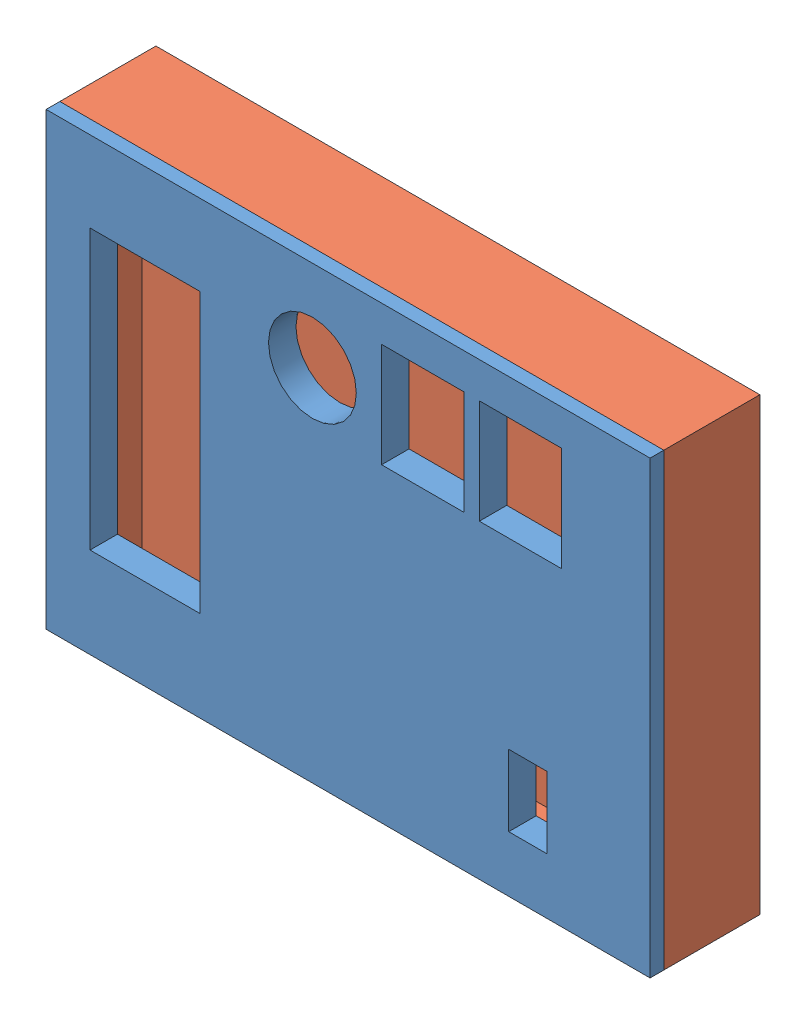
SolidWorks assembly Phase_B_Encloser_ASM, configuration Default. Lengths in mm.
Overall size (110 82 20).
50 component instances, 3 part files, 3 mates.
Components (placement in the parent):
- R_0805_2012Metric.STEP-1: R_0805_2012Metric.STEP [Default] at (136.75 -75.9525 1.63) x (0 1 0) z (0 0 1) size (2 1.2 0.45) (suppressed, hidden)
- PinSocket_2x03_P2.54mm_Vertical.STEP-1: PinSocket_2x03_P2.54mm_Vertical.STEP [Default] at (166.9225 -107.335 1.13) x (-1 0 0) z (0 0 -1) size (5.08 7.62 10.1) (suppressed, hidden)
- C_0603_1608Metric.STEP-1: C_0603_1608Metric.STEP [Default] at (175.1083 -95.3579 1.63) x (0 1 0) z (0 0 1) size (1.6 0.8 0.8) (suppressed, hidden)
- C_0603_1608Metric.STEP-2: C_0603_1608Metric.STEP [Default] at (167.3681 -95.3139 1.63) x (0 1 0) z (0 0 1) size (1.6 0.8 0.8) (suppressed, hidden)
- R_0603_1608Metric.STEP-1: R_0603_1608Metric.STEP [Default] at (178.1154 -121.5005 1.63) size (1.6 0.8 0.45) (suppressed, hidden)
- R_0805_2012Metric.STEP-2: R_0805_2012Metric.STEP [Default] at (164.6638 -86.8628 1.63) size (2 1.2 0.45) (suppressed, hidden)
- USB_Mini-B_Lumberg_2486_01_Horizontal.STEP-1: USB_Mini-B_Lumberg_2486_01_Horizontal.STEP [Default] at (156.7225 -119.07 1.63) size (9.9 9.21 5) (suppressed, hidden)
- SOT-23-5.STEP-1: SOT-23-5.STEP [Default] at (160.6831 -79.2295 1.63) x (0 -1 0) z (0 0 1) size (2.8 2.9 1.55) (suppressed, hidden)
- R_0805_2012Metric.STEP-3: R_0805_2012Metric.STEP [Default] at (124.46 -81.28 1.63) size (2 1.2 0.45) (suppressed, hidden)
- TQFP-44_10x10mm_P0.8mm.STEP-1: TQFP-44_10x10mm_P0.8mm.STEP [Default] at (154.94 -91.44 1.63) x (0 1 0) z (0 0 1) size (12 12 1.1) (suppressed, hidden)
- LED_0805_2012Metric.STEP-1: LED_0805_2012Metric.STEP [Default] at (136.66 -80.3425 1.63) x (0 1 0) z (0 0 1) size (2 1.25 1.1) (suppressed, hidden)
- C_0603_1608Metric.STEP-3: C_0603_1608Metric.STEP [Default] at (164.6143 -92.9198 1.63) size (1.6 0.8 0.8) (suppressed, hidden)
- CA56-12EWA.STEP-1: CA56-12EWA.STEP [Default] at (101.6 -81.28 1.63) size (19 50.3 12.2) (suppressed, hidden)
- C_0603_1608Metric.STEP-4: C_0603_1608Metric.STEP [Default] at (160.3412 -83.2998 1.63) x (-1 0 0) z (0 0 1) size (1.6 0.8 0.8) (suppressed, hidden)
- TSSOP-16_4.4x5mm_P0.65mm.STEP-1: TSSOP-16_4.4x5mm_P0.65mm.STEP [Default] at (137.16 -93.98 1.63) size (6.4 5 1.1) (suppressed, hidden)
- PTS125_SMD_Button.STEP-1: PTS125_SMD_Button.STEP [Default] at (177.0425 -64.155 1.63) x (0 1 0) z (1 0 0) size (12 4.3 15.3) (suppressed, hidden)
- C_0603_1608Metric.STEP-5: C_0603_1608Metric.STEP [Default] at (171.2411 -95.3579 1.63) x (0 1 0) z (0 0 1) size (1.6 0.8 0.8) (suppressed, hidden)
- R_0603_1608Metric.STEP-2: R_0603_1608Metric.STEP [Default] at (171.895 -101.6 1.63) size (1.6 0.8 0.45) (suppressed, hidden)
- C_0603_1608Metric.STEP-6: C_0603_1608Metric.STEP [Default] at (135.1928 -99.8408 1.63) x (-1 0 0) z (0 0 1) size (1.6 0.8 0.8) (suppressed, hidden)
- C_0805_2012Metric.STEP-1: C_0805_2012Metric.STEP [Default] at (177.4051 -95.4592 1.63) x (0 1 0) z (0 0 1) size (2 1.25 1.25) (suppressed, hidden)
- R_0805_2012Metric.STEP-4: R_0805_2012Metric.STEP [Default] at (124.46 -96.93 1.63) size (2 1.2 0.45) (suppressed, hidden)
- R_0805_2012Metric.STEP-5: R_0805_2012Metric.STEP [Default] at (124.46 -99.88 1.63) size (2 1.2 0.45) (suppressed, hidden)
- Buzzer_12x9.5RM7.6.STEP-1: Buzzer_12x9.5RM7.6.STEP [Default] at (139.7 -67.955 1.63) x (0 1 0) z (0 0 1) size (12 12 12.53) (suppressed, hidden)
- R_0603_1608Metric.STEP-3: R_0603_1608Metric.STEP [Default] at (164.621 -94.7272 1.63) x (-1 0 0) z (0 0 1) size (1.6 0.8 0.45) (suppressed, hidden)
- LED_0805_2012Metric.STEP-2: LED_0805_2012Metric.STEP [Default] at (139.7 -80.3425 1.63) x (0 1 0) z (0 0 1) size (2 1.25 1.1) (suppressed, hidden)
- R_0603_1608Metric.STEP-4: R_0603_1608Metric.STEP [Default] at (157.3461 -113.1038 1.63) x (0 1 0) z (0 0 1) size (1.6 0.8 0.45) (suppressed, hidden)
- R_0805_2012Metric.STEP-6: R_0805_2012Metric.STEP [Default] at (164.6674 -88.9903 1.63) size (2 1.2 0.45) (suppressed, hidden)
- C_0603_1608Metric.STEP-7: C_0603_1608Metric.STEP [Default] at (173.1422 -95.3579 1.63) x (0 1 0) z (0 0 1) size (1.6 0.8 0.8) (suppressed, hidden)
- C_0603_1608Metric.STEP-8: C_0603_1608Metric.STEP [Default] at (183.7777 -121.5005 1.63) size (1.6 0.8 0.8) (suppressed, hidden)
- Crystal_SMD_Abracon_ABM8G-4Pin_3.2x2.5mm.STEP-1: Crystal_SMD_Abracon_ABM8G-4Pin_3.2x2.5mm.STEP [Default] at (160.167 -106.8176 1.63) x (0 1 0) z (0 0 1) size (3.2 2.5 0.64) (suppressed, hidden)
- R_0805_2012Metric.STEP-7: R_0805_2012Metric.STEP [Default] at (124.46 -78.33 1.63) size (2 1.2 0.45) (suppressed, hidden)
- R_0805_2012Metric.STEP-8: R_0805_2012Metric.STEP [Default] at (139.7 -75.9525 1.63) x (0 1 0) z (0 0 1) size (2 1.2 0.45) (suppressed, hidden)
- R_0805_2012Metric.STEP-9: R_0805_2012Metric.STEP [Default] at (124.46 -93.98 1.63) size (2 1.2 0.45) (suppressed, hidden)
- C_0603_1608Metric.STEP-9: C_0603_1608Metric.STEP [Default] at (164.6119 -91.194 1.63) x (-1 0 0) z (0 0 1) size (1.6 0.8 0.8) (suppressed, hidden)
- C_0603_1608Metric.STEP-10: C_0603_1608Metric.STEP [Default] at (147.6552 -103.0061 1.63) x (0 -1 0) z (0 0 1) size (1.6 0.8 0.8) (suppressed, hidden)
- C_0603_1608Metric.STEP-11: C_0603_1608Metric.STEP [Default] at (164.2172 -77.2255 1.63) x (0 -1 0) z (0 0 1) size (1.6 0.8 0.8) (suppressed, hidden)
- C_0603_1608Metric.STEP-12: C_0603_1608Metric.STEP [Default] at (169.3071 -95.3345 1.63) x (0 1 0) z (0 0 1) size (1.6 0.8 0.8) (suppressed, hidden)
- C_0603_1608Metric.STEP-13: C_0603_1608Metric.STEP [Default] at (156.1028 -99.9047 1.63) x (0 1 0) z (0 0 1) size (1.6 0.8 0.8) (suppressed, hidden)
- SOT-23-6.STEP-1: SOT-23-6.STEP [Default] at (156.0168 -106.7769 1.63) x (0 1 0) z (0 0 1) size (2.8 2.9 1.55) (suppressed, hidden)
- R_0805_2012Metric.STEP-10: R_0805_2012Metric.STEP [Default] at (124.46 -91.03 1.63) size (2 1.2 0.45) (suppressed, hidden)
- R_0805_2012Metric.STEP-11: R_0805_2012Metric.STEP [Default] at (124.46 -84.23 1.63) size (2 1.2 0.45) (suppressed, hidden)
- C_0603_1608Metric.STEP-14: C_0603_1608Metric.STEP [Default] at (166.5378 -77.2117 1.63) x (0 -1 0) z (0 0 1) size (1.6 0.8 0.8) (suppressed, hidden)
- R_0805_2012Metric.STEP-12: R_0805_2012Metric.STEP [Default] at (124.46 -87.18 1.63) size (2 1.2 0.45) (suppressed, hidden)
- PinSocket_2x04_P2.54mm_Vertical.STEP-1: PinSocket_2x04_P2.54mm_Vertical.STEP [Default] at (179.5825 -109.875 1.63) size (5.08 10.16 10.1) (suppressed, hidden)
- LED_0805_2012Metric.STEP-3: LED_0805_2012Metric.STEP [Default] at (184.4796 -109.4399 1.63) size (2 1.25 1.1) (suppressed, hidden)
- R_0603_1608Metric.STEP-5: R_0603_1608Metric.STEP [Default] at (155.706 -113.0772 1.63) x (0 1 0) z (0 0 1) size (1.6 0.8 0.45) (suppressed, hidden)
- PTS125_SMD_Button.STEP-2: PTS125_SMD_Button.STEP [Default] at (159.2625 -64.155 1.63) x (0 1 0) z (1 0 0) size (12 4.3 15.3) (suppressed, hidden)
- PCB.STEP-1: PCB.STEP [Default] at origin (suppressed, hidden)
- Enclosure_Part_Two-1: Enclosure_Part_Two [Default] at (146.2275 -89.1522 14.2277) x (1 0 0) z (0 0 -1) size (110 82 5)
- Encloser_Part_One-1: Encloser_Part_One [Default] at (146.2275 -89.1522 -5.7723) size (110 82 17.5)
Mates (geometry in assembly coordinates):
- Coincident1: coincident anti-aligned: plane of Enclosure_Part_Two-1 through (146.1152 -88.5497 14.0488) normal (0 0 -1); line of Encloser_Part_One-1 through (224.8768 -47.6092 14.0488) axis (-1 0 0)
- Coincident2: coincident: point of Enclosure_Part_Two-1; unknown of Encloser_Part_One-1
- Distance1: distance = 1 mm: unknown of PinSocket_2x03_P2.54mm_Vertical.STEP-1/SOLID-0.STEP-1; unknown of Encloser_Part_One-1
